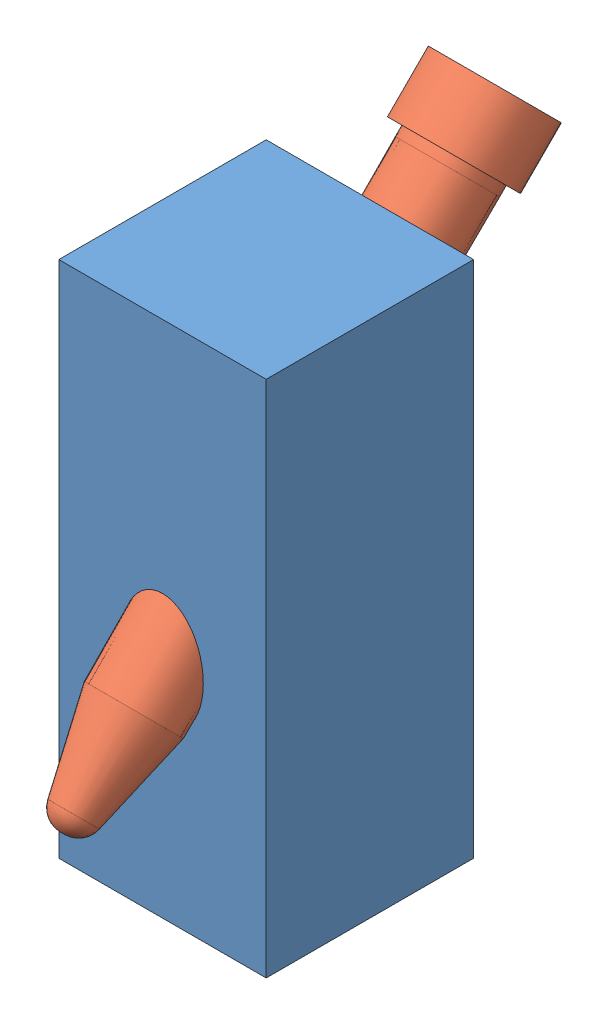
SolidWorks assembly test tube block v3, configuration Default. Lengths in mm.
Overall size (40 117.34 103.7).
2 component instances, 2 part files, 2 mates.
Components (placement in the parent):
- block v3-1: block v3 [Default] at (-18.3301 -23.9534 15.0108) size (40 100 40)
- test tube v3-1: test tube v3 [Default] at (1.6699 51.229 -49.1053) x (0.504634 0.610469 0.610469) z (-0.863333 0.35683 0.35683) size (21 117.93 21)
Mates (geometry in assembly coordinates):
- Concentric4: concentric aligned: cone of block v3-1 through (1.6699 -18.4203 20.544) axis (0 -0.707107 0.707107); cone of test tube v3-1 through (1.6699 42.0719 -39.9483) axis (0 -0.707107 0.707107)
- Tangent1: tangent: plane of block v3-1 through (-18.3301 -55.9534 15.0108) normal (0 0 1); circle of test tube v3-1
